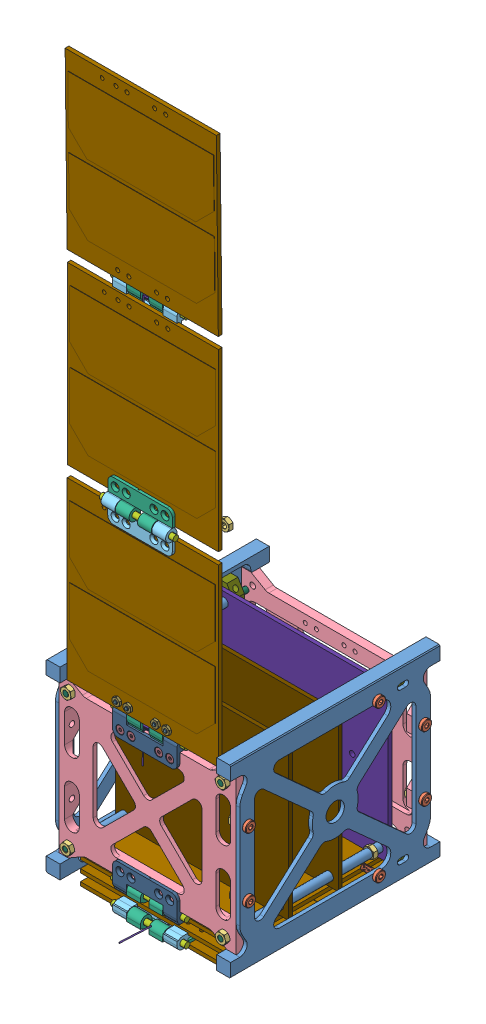
SolidWorks assembly 1U_Chassis, configuration Default. Lengths in mm.
Overall size (102.57 397.77 126.04).
88 component instances, 19 part files, 57 mates.
Components (placement in the parent):
- X-Face-1: X-Face [Default] at (6.5247 99.6979 78.5413) size (7.5 100 113.5)
- X-Face-2: X-Face [Default] at (106.5247 99.6979 78.5413) x (-1 0 0) z (0 0 1) size (7.5 100 113.5)
- 92855A309_18-8 Stainless Steel Low-Profile Socket Head Screws-1: 92855A309_18-8 Stainless Steel Low-Profile Socket Head Screws [92855A309] at (98.5247 117.1979 126.2913) x (0 0 1) z (-1 0 0) size (5.5 5.5 10.17)
- 90685A037_High-Strength Steel Hex Nut-1: 90685A037_High-Strength Steel Hex Nut [90685A037] at (100.3247 117.1979 126.2913) x (0 0 1) z (-1 0 0) size (5.5 6.35 2.69)
- 92855A309_18-8 Stainless Steel Low-Profile Socket Head Screws-2: 92855A309_18-8 Stainless Steel Low-Profile Socket Head Screws [92855A309] at (98.5247 82.1979 126.2913) x (0 0.91884 0.39463) z (-1 0 0) size (5.5 5.5 10.17)
- 90685A037_High-Strength Steel Hex Nut-2: 90685A037_High-Strength Steel Hex Nut [90685A037] at (100.8247 82.1979 126.2913) x (0 -0.924225 -0.381849) z (1 0 0) size (5.5 6.35 2.69)
- 92855A309_18-8 Stainless Steel Low-Profile Socket Head Screws-3: 92855A309_18-8 Stainless Steel Low-Profile Socket Head Screws [92855A309] at (98.5247 117.1979 30.7913) x (0 0.937066 0.349151) z (-1 0 0) size (5.5 5.5 10.17)
- 92855A309_18-8 Stainless Steel Low-Profile Socket Head Screws-4: 92855A309_18-8 Stainless Steel Low-Profile Socket Head Screws [92855A309] at (98.5247 82.1979 30.7913) x (0 0.549538 0.835469) z (-1 0 0) size (5.5 5.5 10.17)
- 90685A037_High-Strength Steel Hex Nut-3: 90685A037_High-Strength Steel Hex Nut [90685A037] at (103.4151 117.1979 30.7913) x (0 0 1) z (-1 0 0) size (5.5 6.35 2.69)
- 90685A037_High-Strength Steel Hex Nut-4: 90685A037_High-Strength Steel Hex Nut [90685A037] at (100.3247 82.1979 30.7913) x (0 0 1) z (-1 0 0) size (5.5 6.35 2.69)
- Z-Face-1: Z-Face [Default] at (56.5247 99.6979 26.7913) x (1 0 0) z (0 -1 0) size (96 8 84.8)
- Hinge_Assembly-1: Hinge_Assembly [Default] at (12.1786 13.5735 147.3729) x (0 0 -1) z (1 0 0) size (123.29 27.85 82)
  - H2-1: H2 [Default] at (18.5816 33.4244 26.846) size (14.1 6.1 35)
  - H1-1: H1 [Default] at (18.5816 33.4244 54.096) x (1 0 0) z (0 0 -1) size (14.2 6.2 35)
  - PIN-1: PIN [Default] at (18.5816 33.4244 24.346) x (0.225287 0.974292 0) z (0 0 1) size (3 3 40)
  - 9271K599_Torsion Spring-1: 9271K599_Torsion Spring [9271K599] at (18.6325 33.0979 47.4102) x (-0.008726 0.008727 0.999924) z (0.999962 0 0.008727) size (5.82 4.73 38.09)
  - Solar_Panel_FULL-1: Solar_Panel_FULL [Default] at (69.1316 35.4744 44.346) x (1 0 0) z (0 1 0) size (95 82 2.2)
  - Solar_Panel_FULL-2: Solar_Panel_FULL [Default] at (69.1816 31.3244 44.346) x (-1 0 0) z (0 -1 0) size (95 82 2.2)
  - H1-2: H1 [Default] at (119.7316 39.5744 34.596) x (-1 0 0) z (0 0 1) size (14.2 6.2 35)
  - H2-2: H2 [Default] at (119.7316 39.5744 61.846) x (-1 0 0) z (0 0 -1) size (14.1 6.1 35)
  - Solar_Panel_FULL-3: Solar_Panel_FULL [Default] at (69.1816 43.6244 44.346) x (-1 0 0) z (0 -1 0) size (95 82 2.2)
  - H1-3: H1 [Default] at (18.5816 45.7244 54.096) x (1 0 0) z (0 0 -1) size (14.2 6.2 35)
  - PIN-2: PIN [Default] at (18.5816 45.7244 24.346) size (3 3 40)
  - H2_Chassis-1: H2_Chassis [Default] at (18.5816 45.7244 26.846) x (0 1 0) z (0 0 1) size (14.25 6 35)
  - M2x5_92125A051_18-8 Stainless Steel Hex Drive Flat Head Screw (1)-2: M2x5_92125A051_18-8 Stainless Steel Hex Drive Flat Head Screw (1) [92125A051] at (25.6816 42.4844 30.846) x (0 0 1) z (0 1 0) size (4 4 5.21)
  - M2 Thin_90710A020_18-8 Stainless Steel Thin Hex Nut-1: M2 Thin_90710A020_18-8 Stainless Steel Thin Hex Nut [90710A020] at (25.6816 40.9244 30.846) size (4 1.51 4.62)
- Hinge_Assembly(deployed)-1: Hinge_Assembly(deployed) [Default] at (100.8707 360.9795 95.3669) x (0 -1 0) z (-1 0 0) size (319.45 14.54 82)
  - H2-1: H2 [Default] at (18.5816 33.4244 26.846) size (14.1 6.1 35)
  - H1-1: H1 [Default] at (18.5816 33.4244 54.096) x (-0.999939 0.011061 0) z (0 0 -1) size (14.2 6.2 35)
  - PIN-1: PIN [Default] at (18.5816 33.4244 24.346) x (0.225287 0.974292 0) z (0 0 1) size (3 3 40)
  - 9271K599_Torsion Spring-1: 9271K599_Torsion Spring [9271K599] at (18.6062 33.1334 42.5303) x (-0.008726 0.008727 0.999924) z (0.999962 0 0.008727) size (5.82 4.73 38.09)
  - Solar_Panel_FULL-1: Solar_Panel_FULL [Default] at (69.1316 35.4744 44.346) x (1 0 0) z (0 1 0) size (95 82 2.2)
  - Solar_Panel_FULL-2: Solar_Panel_FULL [Default] at (-31.992 36.084 44.346) x (0.999939 -0.011061 0) z (0.011061 0.999939 0) size (95 82 2.2)
  - H1-2: H1 [Default] at (119.7316 39.5744 34.596) x (-1 0 0) z (0 0 1) size (14.2 6.2 35)
  - H2-2: H2 [Default] at (119.7316 39.5744 61.846) x (1 0 0) z (0 0 -1) size (14.1 6.1 35)
  - Solar_Panel_FULL-3: Solar_Panel_FULL [Default] at (170.2816 35.5244 44.346) x (1 0 0) z (0 1 0) size (95 82 2.2)
  - H1-3: H1 [Default] at (220.8816 33.4244 54.096) x (-1 0 0) z (0 0 -1) size (14.2 6.2 35)
  - PIN-2: PIN [Default] at (220.8816 33.4244 24.346) size (3 3 40)
  - PIN-3: PIN [Default] at (119.7316 39.5744 24.346) size (3 3 40)
  - H2_Chassis-1: H2_Chassis [Default] at (220.8816 33.4244 26.846) size (14.25 6 35)
  - 92125A054_18-8 Stainless Steel Hex Drive Flat Head Screw-1: 92125A054_18-8 Stainless Steel Hex Drive Flat Head Screw [92125A054] at (228.0066 32.2844 36.846) x (1 0 0) z (0 1 0) size (4 4 8.23)
  - 92125A054_18-8 Stainless Steel Hex Drive Flat Head Screw-2: 92125A054_18-8 Stainless Steel Hex Drive Flat Head Screw [92125A054] at (228.0066 32.2844 57.846) x (1 0 0) z (0 1 0) size (4 4 8.23)
  - 92125A054_18-8 Stainless Steel Hex Drive Flat Head Screw-3: 92125A054_18-8 Stainless Steel Hex Drive Flat Head Screw [92125A054] at (228.0066 32.2844 51.846) x (1 0 0) z (0 1 0) size (4 4 8.23)
  - 92125A054_18-8 Stainless Steel Hex Drive Flat Head Screw-4: 92125A054_18-8 Stainless Steel Hex Drive Flat Head Screw [92125A054] at (228.0066 32.2844 30.846) x (1 0 0) z (0 1 0) size (4 4 8.23)
  - 92125A051_18-8 Stainless Steel Hex Drive Flat Head Screw-1: 92125A051_18-8 Stainless Steel Hex Drive Flat Head Screw [92125A051] at (213.7816 36.6644 36.846) x (1 0 0) z (0 -1 0) size (4 4 5.21)
  - 92125A051_18-8 Stainless Steel Hex Drive Flat Head Screw-2: 92125A051_18-8 Stainless Steel Hex Drive Flat Head Screw [92125A051] at (213.7816 36.6644 51.846) x (1 0 0) z (0 -1 0) size (4 4 5.21)
  - 92125A051_18-8 Stainless Steel Hex Drive Flat Head Screw-3: 92125A051_18-8 Stainless Steel Hex Drive Flat Head Screw [92125A051] at (213.7816 36.6644 30.846) x (1 0 0) z (0 -1 0) size (4 4 5.21)
  - 92125A051_18-8 Stainless Steel Hex Drive Flat Head Screw-4: 92125A051_18-8 Stainless Steel Hex Drive Flat Head Screw [92125A051] at (213.7816 36.6644 57.846) x (1 0 0) z (0 -1 0) size (4 4 5.21)
  - M2 Thin_90710A020_18-8 Stainless Steel Thin Hex Nut-1: M2 Thin_90710A020_18-8 Stainless Steel Thin Hex Nut [90710A020] at (213.7816 38.1244 36.846) x (0.988814 0 0.149152) z (-0.149152 0 0.988814) size (4 1.51 4.62)
  - M2 Thin_90710A020_18-8 Stainless Steel Thin Hex Nut-2: M2 Thin_90710A020_18-8 Stainless Steel Thin Hex Nut [90710A020] at (213.7816 38.1244 51.846) x (0.935029 0 0.354571) z (-0.354571 0 0.935029) size (4 1.51 4.62)
  - M2 Thin_90710A020_18-8 Stainless Steel Thin Hex Nut-3: M2 Thin_90710A020_18-8 Stainless Steel Thin Hex Nut [90710A020] at (213.7816 38.1244 57.846) x (-0.837169 0 -0.546944) z (-0.546944 0 0.837169) size (4 1.51 4.62)
  - M2 Thin_90710A020_18-8 Stainless Steel Thin Hex Nut-4: M2 Thin_90710A020_18-8 Stainless Steel Thin Hex Nut [90710A020] at (213.7816 38.1244 30.846) x (-0.837169 0 -0.546944) z (-0.546944 0 0.837169) size (4 1.51 4.62)
  - 9271K599_Torsion Spring-2: 9271K599_Torsion Spring [9271K599] at (220.8861 33.1618 46.1681) x (-0.008726 0.000076 -0.999962) z (-0.999924 0.008726 0.008727) size (5.82 4.73 38.09)
- Z-Face-2: Z-Face [Default] at (56.5247 99.6979 130.2913) x (-1 0 0) z (0 -1 0) size (96 8 84.8)
- 90685A037_High-Strength Steel Hex Nut-5: 90685A037_High-Strength Steel Hex Nut [90685A037] at (14.5247 136.1979 131.4913) x (-0.357096 -0.934068 0) z (0 0 -1) size (5.5 6.35 2.69)
- 90685A037_High-Strength Steel Hex Nut-6: 90685A037_High-Strength Steel Hex Nut [90685A037] at (14.5247 63.1979 131.8682) x (-0.923728 -0.383049 0) z (0 0 -1) size (5.5 6.35 2.69)
- 90685A037_High-Strength Steel Hex Nut-7: 90685A037_High-Strength Steel Hex Nut [90685A037] at (98.5247 136.1979 131.5827) x (-0.923728 -0.383049 0) z (0 0 -1) size (5.5 6.35 2.69)
- 90685A037_High-Strength Steel Hex Nut-8: 90685A037_High-Strength Steel Hex Nut [90685A037] at (98.5247 63.1979 131.646) x (-0.923728 -0.383049 0) z (0 0 -1) size (5.5 6.35 2.69)
- 92855A309_18-8 Stainless Steel Low-Profile Socket Head Screws-5: 92855A309_18-8 Stainless Steel Low-Profile Socket Head Screws [92855A309] at (98.5247 140.6979 55.7913) x (0 -0.400827 -0.916154) z (-1 0 0) size (5.5 5.5 10.17)
- 92855A309_18-8 Stainless Steel Low-Profile Socket Head Screws-6: 92855A309_18-8 Stainless Steel Low-Profile Socket Head Screws [92855A309] at (98.5247 58.6979 55.7913) x (0 0.663174 0.748465) z (-1 0 0) size (5.5 5.5 10.17)
- 90685A037_High-Strength Steel Hex Nut-9: 90685A037_High-Strength Steel Hex Nut [90685A037] at (98.5247 136.1979 51.4102) size (5.5 6.35 2.69)
- 90685A037_High-Strength Steel Hex Nut-10: 90685A037_High-Strength Steel Hex Nut [90685A037] at (8.823 166.6381 40.1026) size (5.5 6.35 2.69)
- 90685A037_High-Strength Steel Hex Nut-11: 90685A037_High-Strength Steel Hex Nut [90685A037] at (14.5247 63.1979 51.3736) size (5.5 6.35 2.69)
- 90685A037_High-Strength Steel Hex Nut-12: 90685A037_High-Strength Steel Hex Nut [90685A037] at (98.5247 63.1979 51.3176) size (5.5 6.35 2.69)
- PCB_Stack_3-1: PCB_Stack_3 [Default] at (98.5247 136.1979 34.7913) x (1 -0.000003 0) z (-0.000003 -1 0) size (96 98 88)
  - PCB_Rod_2-1: PCB_Rod_2 [Default] at origin size (3 98 3)
  - PCB_Rod_2-2: PCB_Rod_2 [Default] at (-84 0 0.0003) x (-0.139284 0 0.990253) z (-0.990253 0 -0.139284) size (3 98 3)
  - PCB_Rod_2-3: PCB_Rod_2 [Default] at (-83.9998 0 73.0003) x (0.037489 0 0.999297) z (-0.999297 0 0.037489) size (3 98 3)
  - PCB_Rod_2-4: PCB_Rod_2 [Default] at (0.0002 0 73) x (0.981991 0 -0.188925) z (0.188925 0 0.981991) size (3 98 3)
  - Mounting_Standoff-1: Mounting_Standoff [Default] at (-41.9999 10 36.5001) x (1 0 -0.000003) z (0 -1 0) size (9 10.5 6)
  - PCB_Battery-1: PCB_Battery [Default] at (-41.9999 10 36.5001) x (-1 0 0.000003) z (-0.000003 0 -1) size (94 2 83)
  - PCB-1: PCB [Default] at (-41.9999 64 36.5001) x (1 0 -0.000003) z (0.000003 0 1) size (94 2 83)
  - PCB-2: PCB [Default] at (-41.9999 37 36.5001) x (1 0 -0.000003) z (0.000003 0 1) size (94 2 83)
  - Mounting_Standoff-2: Mounting_Standoff [Default] at (-41.9999 4 36.5001) x (-1 0 0.000003) z (0 1 0) size (9 10.5 6)
  - Mounting_Standoff-3: Mounting_Standoff [Default] at (-41.9999 4 36.5001) x (1 0 -0.000003) z (0 1 0) size (9 10.5 6)
  - Mounting_Standoff-4: Mounting_Standoff [Default] at (-41.9999 10 36.5001) x (-1 0 0.000003) z (0 -1 0) size (9 10.5 6)
  - Aluminum Unthreaded Spacer_Battery-1: Aluminum Unthreaded Spacer_Battery [94669A105] at (0 24.5 0) x (0.317635 0 -0.948213) z (0 1 0) size (4.5 4.5 25)
  - Aluminum Unthreaded Spacer_Battery-2: Aluminum Unthreaded Spacer_Battery [94669A105] at (0 51.5 0) x (0.317635 0 -0.948213) z (0 1 0) size (4.5 4.5 25)
  - Aluminum Unthreaded Spacer_Battery-3: Aluminum Unthreaded Spacer_Battery [94669A105] at (0 78.5 0) x (-0.841831 0 -0.539741) z (0 1 0) size (4.5 4.5 25)
  - Aluminum Unthreaded Spacer_Battery-4: Aluminum Unthreaded Spacer_Battery [94669A105] at (0.0002 24.5 73) x (0.317635 0 -0.948213) z (0 1 0) size (4.5 4.5 25)
  - Aluminum Unthreaded Spacer_Battery-5: Aluminum Unthreaded Spacer_Battery [94669A105] at (0.0002 51.5 73) x (0.317635 0 -0.948213) z (0 1 0) size (4.5 4.5 25)
  - Aluminum Unthreaded Spacer_Battery-6: Aluminum Unthreaded Spacer_Battery [94669A105] at (0.0002 78.5 73) x (-0.286549 0 -0.958066) z (0 1 0) size (4.5 4.5 25)
  - Aluminum Unthreaded Spacer_Battery-7: Aluminum Unthreaded Spacer_Battery [94669A105] at (-83.9998 24.5 73.0003) x (0.317635 0 -0.948213) z (0 1 0) size (4.5 4.5 25)
  - Aluminum Unthreaded Spacer_Battery-8: Aluminum Unthreaded Spacer_Battery [94669A105] at (-83.9998 51.5 73.0003) x (0.317635 0 -0.948213) z (0 1 0) size (4.5 4.5 25)
  - Aluminum Unthreaded Spacer_Battery-9: Aluminum Unthreaded Spacer_Battery [94669A105] at (-83.9998 78.5 73.0003) x (-0.883236 0 -0.468929) z (0 1 0) size (4.5 4.5 25)
  - Aluminum Unthreaded Spacer_Battery-10: Aluminum Unthreaded Spacer_Battery [94669A105] at (-84 51.5 0.0003) x (0.317635 0 -0.948213) z (0 1 0) size (4.5 4.5 25)
  - Aluminum Unthreaded Spacer_Battery-11: Aluminum Unthreaded Spacer_Battery [94669A105] at (-84 78.5 0.0003) x (-0.872408 0 -0.488777) z (0 1 0) size (4.5 4.5 25)
  - Aluminum Unthreaded Spacer_Battery-12: Aluminum Unthreaded Spacer_Battery [94669A105] at (-84 24.5 0.0003) x (0.317635 0 -0.948213) z (0 1 0) size (4.5 4.5 25)
Mates (geometry in assembly coordinates):
- Coincident2: coincident anti-aligned: plane of X-Face-1 through (8.5247 57.1979 135.2913) normal (1 0 0); plane of S2-1 through (8.5247 142.1979 184.9271) normal (-1 0 0)
- Coincident3: coincident anti-aligned: plane of X-Face-1 through (8.5247 142.1979 135.2913) normal (0 -1 0); plane of S2-1 through (56.5247 142.1979 135.6771) normal (0 1 0)
- Coincident5: coincident anti-aligned: plane of S2-1 through (56.5247 142.1979 135.6771) normal (0 1 0); plane of X-Face-2 through (99.0247 142.1979 135.2913) normal (0 -1 0)
- Coincident6: coincident anti-aligned: plane of S2-1 through (104.5247 142.1979 184.9271) normal (1 0 0); plane of X-Face-2 through (104.5247 142.1979 135.2913) normal (-1 0 0)
- Coincident8: coincident anti-aligned: plane of X-Face-1 through (14.0247 57.1979 135.2913) normal (0 1 0); plane of S2-2 through (56.5247 57.1979 135.1691) normal (0 -1 0)
- Coincident9: coincident anti-aligned: plane of X-Face-1 through (8.5247 57.1979 135.2913) normal (1 0 0); plane of S2-2 through (8.5247 59.1979 184.4191) normal (-1 0 0)
- Coincident14: coincident aligned: plane of X-Face-1 through (14.0247 149.6979 135.2913) normal (0 1 0); plane of X-Face-2 through (106.5247 149.6979 135.2913) normal (0 1 0)
- Coincident16: coincident anti-aligned: plane of X-Face-1 through (8.5247 57.1979 135.2913) normal (1 0 0); plane of Z-2 through (8.5247 57.1979 130.2913) normal (-1 0 0)
- Coincident17: coincident aligned: plane of X-Face-1 through (6.5247 99.6979 130.2913) normal (0 0 1); plane of Z-2 through (104.5247 57.1979 130.2913) normal (0 0 1)
- Coincident18: coincident anti-aligned: plane of X-Face-1 through (14.0247 57.1979 135.2913) normal (0 1 0); plane of Z-2 through (56.5247 57.1979 128.2913) normal (0 -1 0)
- Concentric5: concentric aligned: cylinder of X-Face-2 through (106.5247 117.1979 126.2913) axis (-1 0 0) radius 1.5; cylinder of 92855A309_18-8 Stainless Steel Low-Profile Socket Head Screws-1 through (108.5247 117.1979 126.2913) axis (-1 0 0) radius 2.75
- Coincident19: coincident anti-aligned: plane of X-Face-2 through (106.5247 49.6979 135.2913) normal (1 0 0); plane of 92855A309_18-8 Stainless Steel Low-Profile Socket Head Screws-1 through (106.5247 117.1979 126.2913) normal (-1 0 0)
- Coincident21: coincident anti-aligned: circle of Z-2; circle of 90685A037_High-Strength Steel Hex Nut-1
- Concentric6: concentric aligned: circle of S1-2; circle of 92855A309_18-8 Stainless Steel Low-Profile Socket Head Screws-2
- Concentric7: concentric aligned: cylinder of X-Face-2 through (106.5247 82.1979 126.2913) axis (-1 0 0) radius 1.5; cylinder of 92855A309_18-8 Stainless Steel Low-Profile Socket Head Screws-2 through (108.5247 82.1979 126.2913) axis (-1 0 0) radius 2.75
- Coincident22: coincident anti-aligned: plane of X-Face-2 through (106.5247 49.6979 135.2913) normal (1 0 0); plane of 92855A309_18-8 Stainless Steel Low-Profile Socket Head Screws-2 through (106.5247 82.1979 126.2913) normal (-1 0 0)
- Coincident23: coincident anti-aligned: circle of Z-2; circle of 90685A037_High-Strength Steel Hex Nut-2
- Concentric8: concentric aligned: cylinder of X-Face-2 through (106.5247 117.1979 30.7913) axis (-1 0 0) radius 1.5; cylinder of 92855A309_18-8 Stainless Steel Low-Profile Socket Head Screws-3 through (108.5247 117.1979 30.7913) axis (-1 0 0) radius 2.75
- Coincident24: coincident anti-aligned: plane of X-Face-2 through (104.5247 142.1979 135.2913) normal (-1 0 0); plane of Z-2 through (104.5247 57.1979 120.7913) normal (1 0 0)
- Coincident25: coincident anti-aligned: plane of X-Face-2 through (106.5247 49.6979 135.2913) normal (1 0 0); plane of 92855A309_18-8 Stainless Steel Low-Profile Socket Head Screws-3 through (106.5247 117.1979 30.7913) normal (-1 0 0)
- Concentric9: concentric aligned: cylinder of X-Face-2 through (106.5247 82.1979 30.7913) axis (-1 0 0) radius 1.5; cylinder of 92855A309_18-8 Stainless Steel Low-Profile Socket Head Screws-4 through (108.5247 82.1979 30.7913) axis (-1 0 0) radius 2.75
- Coincident26: coincident anti-aligned: plane of X-Face-2 through (106.5247 49.6979 135.2913) normal (1 0 0); plane of 92855A309_18-8 Stainless Steel Low-Profile Socket Head Screws-4 through (106.5247 82.1979 30.7913) normal (-1 0 0)
- Coincident27: coincident anti-aligned: plane of X-Face-2 through (104.5247 142.1979 135.2913) normal (-1 0 0); plane of Z-Face-1 through (104.5247 57.2979 28.7913) normal (1 0 0)
- Distance1: distance = 0 mm aligned: plane of Z-Face-1 through (89.7926 58.2979 26.7913) normal (0 0 -1); plane of X-Face-2 through (106.5247 99.6979 26.7913) normal (0 0 -1)
- Parallel2: parallel aligned: line of Z-Face-1 through (23.2567 62.2979 26.7913) axis (1 0 0); line of Hinge_Assembly-1/H2-3 through (54.9997 70.1979 25.2913) axis (1 0 0)
- Coincident33: coincident anti-aligned: plane of Z-Face-1 through (89.7926 58.2979 26.7913) normal (0 0 -1); plane of Hinge_Assembly-1/H2-3 through (66.5247 70.1979 26.7913) normal (0 0 1)
- Coincident34: coincident aligned: plane of X-Face-1 through (6.5247 99.6979 26.7913) normal (0 0 -1); plane of Z-Face-1 through (89.7926 58.2979 26.7913) normal (0 0 -1)
- Coincident35: coincident: plane of Z-Face-1 through (89.7926 58.2979 26.7913) normal (0 0 -1); plane of Hinge_Assembly-2/H2-3 through (44.0247 128.9479 26.7913) normal (0 0 1)
- Coincident36: coincident: cylinder of Z-Face-1 through (49.0247 132.9729 28.7913) axis (0 0 -1) radius 1.1; circle of Hinge_Assembly-2/H2-3
- Coincident37: coincident anti-aligned: plane of X-Face-1 through (8.5247 57.1979 135.2913) normal (1 0 0); plane of Z-Face-1 through (8.5247 57.2979 28.7913) normal (-1 0 0)
- Parallel3: parallel aligned: line of Z-Face-1 through (89.7926 137.0979 26.7913) axis (-1 0 0); line of Hinge_Assembly-2/H2-3 through (79.0247 128.9479 25.0413) axis (-1 0 0)
- Coincident39: coincident anti-aligned: plane of Z-Face-1 through (89.7926 58.2979 26.7913) normal (0 0 -1); plane of Hinge_Assembly(deployed)-1/H2-3 through (46.5247 129.1979 26.7913) normal (0 0 1)
- Concentric10: concentric aligned: circle of Z2-1; circle of Hinge_Assembly(deployed)-1/H2-3
- Parallel4: parallel aligned: line of Z-Face-1 through (89.7926 137.0979 26.7913) axis (-1 0 0); line of Hinge_Assembly(deployed)-1/H2-3 through (71.0247 129.1979 25.2913) axis (-1 0 0)
- Coincident42: coincident anti-aligned: plane of X-Face-1 through (8.5247 57.1979 135.2913) normal (1 0 0); plane of Z-Face-2 through (8.5247 57.2979 128.2913) normal (-1 0 0)
- Coincident43: coincident aligned: plane of X-Face-1 through (6.5247 99.6979 130.2913) normal (0 0 1); plane of Z-Face-2 through (23.2567 58.2979 130.2913) normal (0 0 1)
- Coincident45: coincident aligned: circle of 90685A037_High-Strength Steel Hex Nut-4; circle of Z2-1
- Concentric12: concentric anti-aligned: circle of 90685A037_High-Strength Steel Hex Nut-3; circle of Z2-1
- Concentric14: concentric aligned: circle of Z2-2; circle of 90685A037_High-Strength Steel Hex Nut-6
- Concentric15: concentric aligned: circle of Z2-2; circle of 90685A037_High-Strength Steel Hex Nut-7
- Concentric16: concentric aligned: circle of Z2-2; circle of 90685A037_High-Strength Steel Hex Nut-8
- Coincident50: coincident anti-aligned: plane of X-Face-2 through (106.5247 49.6979 135.2913) normal (1 0 0); plane of 92855A309_18-8 Stainless Steel Low-Profile Socket Head Screws-5 through (106.5247 140.6979 55.7913) normal (-1 0 0)
- Coincident51: coincident anti-aligned: plane of X-Face-2 through (106.5247 49.6979 135.2913) normal (1 0 0); plane of 92855A309_18-8 Stainless Steel Low-Profile Socket Head Screws-6 through (106.5247 58.6979 55.7913) normal (-1 0 0)
- Coincident52: coincident anti-aligned: cylinder of Z-Face-1 through (70.0247 66.4229 28.7913) axis (0 0 -1) radius 1.1; circle of Hinge_Assembly-1/H2-3
- Coincident56: coincident aligned: cylinder of Hinge_Assembly(deployed)-1/H2_Chassis-1 through (49.0247 132.9729 131.7913) axis (0 0 -1) radius 1.1; circle of Z-Face-2
- Parallel8: parallel aligned: line of Hinge_Assembly(deployed)-1/H2_Chassis-1 through (42.0247 128.8479 131.7913) axis (1 0 0); line of Z-Face-2 through (39.6372 128.9479 130.2913) axis (1 0 0)
- Coincident58: coincident aligned: circle of Hinge_Assembly-1/H2_Chassis-1; circle of Z-Face-2
- Parallel9: parallel aligned: line of Hinge_Assembly-1/H2_Chassis-1 through (71.0247 70.5479 131.7913) axis (-1 0 0); line of Z-Face-2 through (89.7926 62.2979 130.2913) axis (-1 0 0)
- Coincident63: coincident anti-aligned: plane of Hinge_Assembly(deployed)-1/H2_Chassis-1 through (66.5247 128.8479 130.2913) normal (0 0 -1); plane of Z-Face-2 through (23.2567 58.2979 130.2913) normal (0 0 1)
- Concentric24: concentric aligned: circle of Z-Face-2; circle of 90685A037_High-Strength Steel Hex Nut-5
- Coincident64: coincident anti-aligned: plane of Z-Face-2 through (23.2567 58.2979 130.2913) normal (0 0 1); plane of 90685A037_High-Strength Steel Hex Nut-5 through (14.5247 136.1979 130.2913) normal (0 0 -1)
- Coincident65: coincident anti-aligned: circle of X-Face-1; cylinder of Z-Face-1 through (13.5247 82.1979 30.7913) axis (-1 0 0) radius 1.5
- Concentric25: concentric anti-aligned: cylinder of X-Face-1 through (6.5247 117.1979 126.2913) axis (1 0 0) radius 1.5; cylinder of Z-Face-2 through (13.5247 117.1979 126.2913) axis (-1 0 0) radius 1.5
- Coincident66: coincident anti-aligned: circle of 90685A037_High-Strength Steel Hex Nut-1; circle of Z-Face-2
- Concentric26: concentric anti-aligned: cylinder of Z-Face-2 through (98.5247 63.1979 128.2913) axis (0 0 1) radius 1.55; cylinder of PCB_Stack_3-1/PCB_Rod_2-4 through (98.5247 63.1979 132.7913) axis (0 0 -1) radius 1.5
- Coincident67: coincident anti-aligned: plane of Z-Face-2 through (56.5247 99.6979 125.7913) normal (0 0 -1); plane of PCB_Stack_3-1/Aluminum Unthreaded Spacer_Battery-3 through (98.5247 136.1979 125.7913) normal (0 0 1)
- Parallel10: parallel anti-aligned: line of X-Face-2 through (104.5247 127.3952 34.7913) axis (0 -1 0); line of PCB_Stack_3-1/PCB_Battery-1 through (103.5247 58.1979 46.7913) axis (0 1 0)
